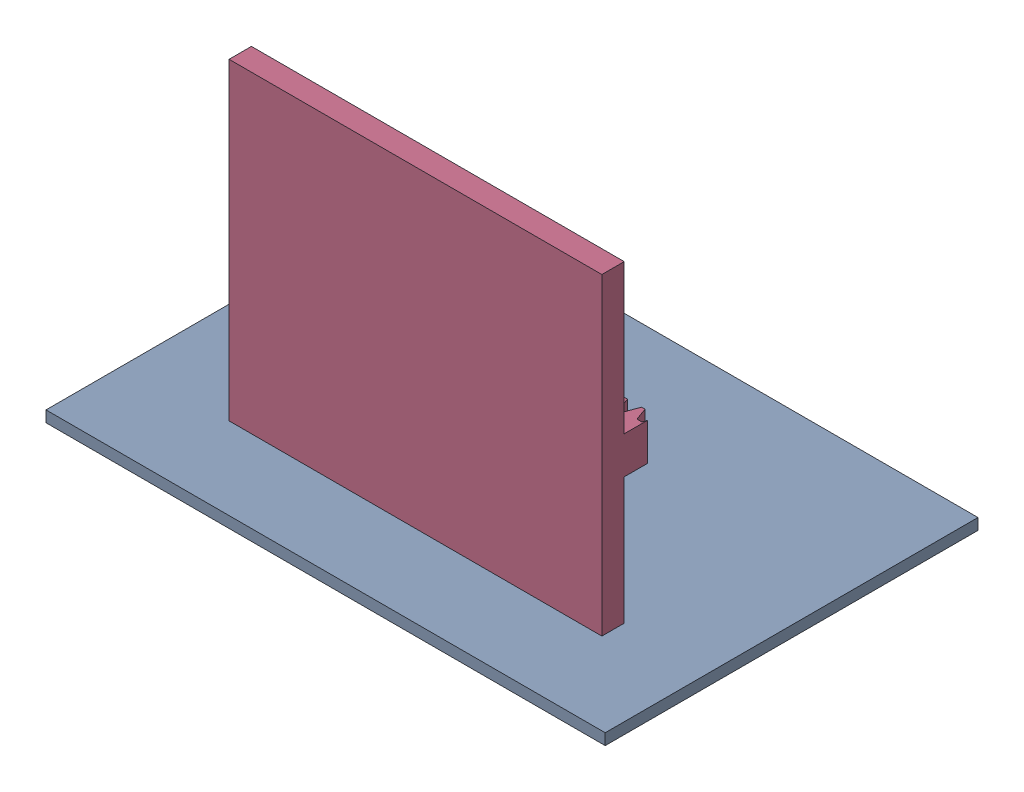
SolidWorks assembly RACKKKAND PINON finalllllll, configuration Default. Lengths in mm.
Overall size (150 87 100).
4 component instances, 4 part files, 12 mates.
Components (placement in the parent):
- base gate-1: base gate [Default] at (-64.4 -45.5001 0) x (0 0 1) z (-1 0 0) size (100 30.2 150)
- head servo-1: head servo [Default] at (0 -20.0001 0) x (-0.691352 0 0.722518) z (0 1 0) size (18.89 7.42 5)
- newgear-1: newgear [Metric - Spur gear 1.5M 20T 20PA 10FW ---S20O20H20L8N] at (0 -10 0) x (0 1 0) z (0.691352 0 -0.722518) size (20 32.71 32.71)
- newrackbta3t assembly-2: newrackbta3t assembly [Metric - Rack-spur - rectangular 1.5M 20PA 10FW 10PH 100L---SAll] at (-37.2958 0 25) x (1 0 0) z (0 1 0) size (100 14.5 84)
Mates (geometry in assembly coordinates):
- Parallel1: parallel: plane of assembly through (0 0 0) normal (0 1 0); plane of base gate-1 through (85.6 -47.0001 0) normal (0 -1 0); plane of assembly
- Concentric2: concentric aligned: cylinder of base gate-1 through (0 -16.8001 0) axis (0 -1 0) radius 2.5; cylinder of head servo-1 through (0 -15.0001 0) axis (0 -1 0) radius 2.5
- Coincident4: coincident anti-aligned: plane of base gate-1 through (0 -20.0001 0) normal (0 1 0); plane of head servo-1 through (0 -20.0001 0) normal (0 -1 0)
- Concentric5: concentric aligned: cylinder of head servo-1 through (0 -15.0001 0) axis (0 -1 0) radius 2.5; cylinder of newgear-1 through (0 10.0001 0) axis (0 -1 0) radius 4
- Perpendicular6: perpendicular: plane of base gate-1 through (85.6 -45.5001 50) normal (0 0 1); plane of newrackbta3t assembly-2 through (-19.7212 -10 24.68) normal (-1 0 0)
- Coincident24: coincident anti-aligned: circle of head servo-1; circle of newgear-1
- Coincident25: coincident anti-aligned: circle of head servo-1; circle of newgear-1
- Coincident26: coincident aligned: plane of newgear-1 through (0 0 0) normal (0 1 0)
- Parallel7: parallel anti-aligned: line of newrackbta3t assembly-2 through (-21.0583 0 14.68) axis (1 0 0)
- Coincident34: coincident aligned: plane of newgear-1 through (0 0 0) normal (0 1 0); plane of newrackbta3t assembly-2 through (-19.7212 0 13.18) normal (0 1 0)
- Coincident35: coincident aligned: line of newrackbta3t assembly-2 through (-19.7212 0 21.68) axis (1 0 0)
- RackPinionMate1: rack pinion = 30 mm: line of newrackbta3t assembly-2 through (-19.7212 40 21.68) axis (1 0 0); circle of newgear-1
